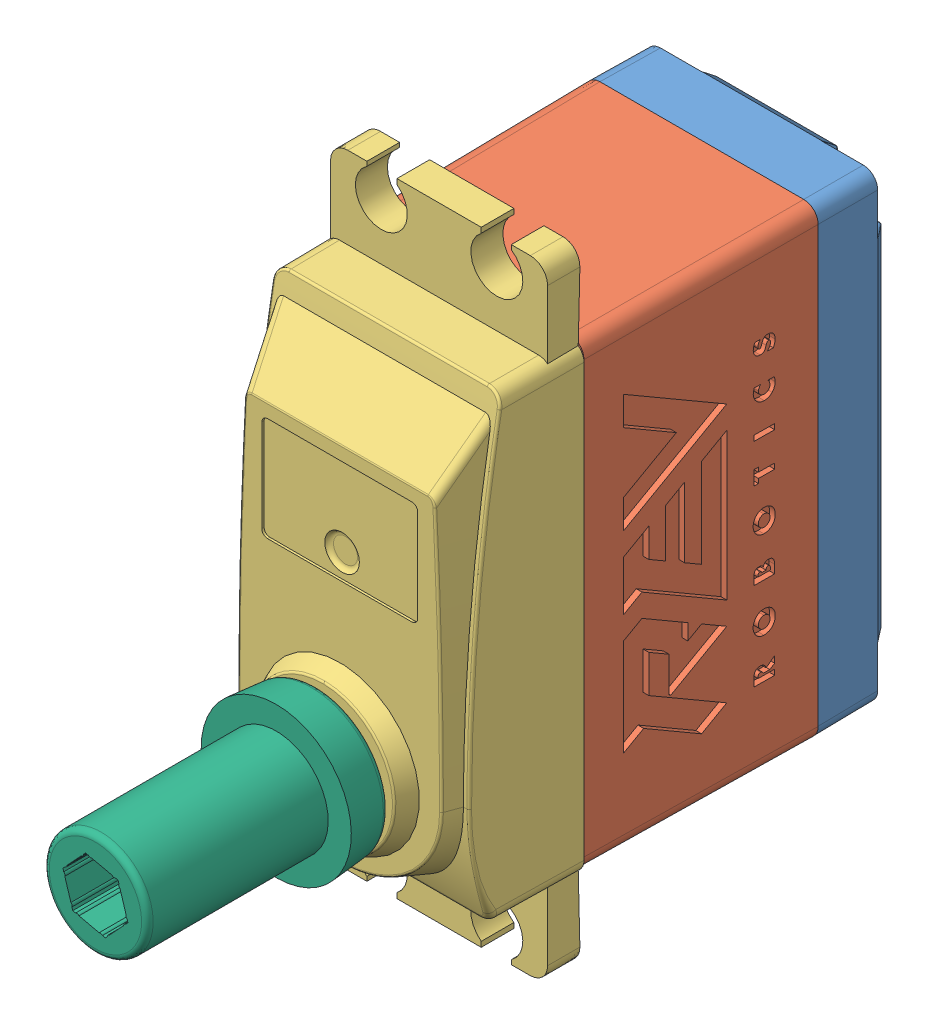
SolidWorks assembly ServoSmartRobotHex, configuration Default. Lengths in mm.
Overall size (21.51 54 59.01).
7 component instances, 6 part files, 3 mates.
Components (placement in the parent):
- PART_ASSEM_ServoSmartRobot-1: PART_ASSEM_ServoSmartRobot [Default] at (61.8284 25.7769 60.7614) size (21.51 54 43.55) (flexible)
  - PART_ServoSmartRobot_A-1: PART_ServoSmartRobot_A [Default] at (-52.3535 19.3227 -48.1464) x (-1 0 0) z (0 0 -1) size (20.15 40.13 8.5)
  - PART_ServoSmartRobot_E-1: PART_ServoSmartRobot_E [Default] at (-52.3531 19.3123 -48.1964) x (-1 0 0) z (0 0 -1) size (20.24 40.15 20.1)
  - PART_ServoSmartRobot_C-1: PART_ServoSmartRobot_C [Default] at (-52.3543 19.0851 -48.2464) x (-1 0 0) z (0 0 -1) size (19.8 54 13.28)
  - PART_ServoSmartRobot_B-1: PART_ServoSmartRobot_B [Default] at (-62.1395 6.7292 -48.1964) x (0.229124 -0.973397 0) z (0 0 -1) size (9 9 4.4)
  - PART_ServoSmartRobot_D-1: PART_ServoSmartRobot_D [Default] at (-52.3543 9.0325 -18.1964) x (-0.296716 0.954966 0) z (0 0 -1) size (17.2 17.19 14.7)
- PART_ServoSmartRobotHex_ServoHexAdapter-1: PART_ServoSmartRobotHex_ServoHexAdapter [Default] at (9.474 34.8093 71.6224) x (-0.296716 0.954966 0) z (0 0 -1) size (13 13 19.16)
Mates (geometry in assembly coordinates):
- Coincident1: coincident anti-aligned: plane of PART_ASSEM_ServoSmartRobot-1/PART_ServoSmartRobot_D-1 through (9.474 34.8093 56.165) normal (0 0 1); plane of PART_ServoSmartRobotHex_ServoHexAdapter-1 through (9.474 34.8093 56.165) normal (0 0 -1)
- Concentric1: concentric anti-aligned: cylinder of PART_ASSEM_ServoSmartRobot-1/PART_ServoSmartRobot_D-1 through (9.474 34.8093 52.7) axis (0 0 -1) radius 2.5; cylinder of PART_ServoSmartRobotHex_ServoHexAdapter-1 through (9.474 34.8093 63.7937) axis (0 0 1) radius 4.5
- Coincident2: coincident aligned: plane of PART_ASSEM_ServoSmartRobot-1/PART_ServoSmartRobot_D-1 through (9.474 34.8093 42.565) normal (-0.296716 0.954966 0); plane of PART_ServoSmartRobotHex_ServoHexAdapter-1 through (9.474 34.8093 71.6224) normal (-0.296716 0.954966 0)
